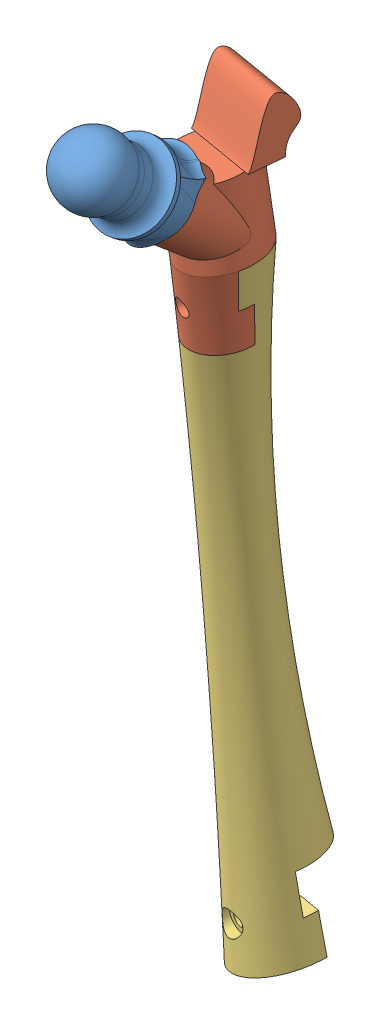
SolidWorks assembly 03_Femur_Right, configuration Default. Lengths in mm.
Overall size (86.13 385.13 137.43).
3 component instances, 3 part files, 6 mates.
Components (placement in the parent):
- 03_01_Femoral_Knob_Right-1: 03_01_Femoral_Knob_Right [Default] at (-102.7139 -439.9992 -170.2167) size (38.14 57.65 59.92)
- 03_02_Femoral_Head_Right-1: 03_02_Femoral_Head_Right [Default] at (-91.4028 -16.6121 -217.2242) x (0.97624 0.052742 0.210175) z (-0.204043 -0.102785 0.973551) size (46.2 104.33 66.31)
- 03_03_Femur_Right-1: 03_03_Femur_Right [Default] at (-90.3595 -320.5161 -249.0909) x (0.97624 0.052742 0.210175) z (-0.204043 -0.102785 0.973551) size (54.81 304.92 50.87)
Mates (geometry in assembly coordinates):
- Coincident2: coincident anti-aligned: plane of 03_02_Femoral_Head_Right-1 through (-127.4345 -37.3213 -229.5916) normal (0.204043 0.102785 -0.973551); plane of 03_03_Femur_Right-1 through (-106.5958 -321.1584 -255.1908) normal (-0.204043 -0.102785 0.973551)
- Concentric1: concentric anti-aligned: cylinder of 03_02_Femoral_Head_Right-1 through (-97.1468 -37.5747 -202.1173) axis (0.204043 0.102785 -0.973551) radius 4.0132; cylinder of 03_03_Femur_Right-1 through (-88.2812 -33.1088 -244.4179) axis (-0.204043 -0.102785 0.973551) radius 3.175
- Concentric2: concentric anti-aligned: cylinder of 03_01_Femoral Knob-1 through (-92.2216 39.7791 -162.301) axis (0 -0.642788 -0.766044) radius 4.953; cylinder of 03_02_Femoral_Head_Right-1 through (-92.2216 3.5358 -205.4941) axis (0 0.642788 0.766044) radius 3.175
- Coincident3: coincident anti-aligned: plane of 03_01_Femoral Knob-1 through (-92.2216 19.8626 -186.0365) normal (0 -0.642788 -0.766044); plane of 03_02_Femoral_Head_Right-1 through (-92.2216 19.8626 -186.0365) normal (0 0.642788 0.766044)
- Coincident4: coincident anti-aligned: plane of 03_02_Femoral_Head_Right-1 through (-126.0448 -56.2438 -231.2981) normal (0.072949 -0.993304 -0.089581); plane of 03_03_Femur_Right-1 through (-126.5737 -56.5072 -228.8076) normal (-0.072949 0.993304 0.089581)
- Lock2: lock: unknown of 03_01_Femoral_Knob_Right-1; unknown of 03_02_Femoral_Head_Right-1
